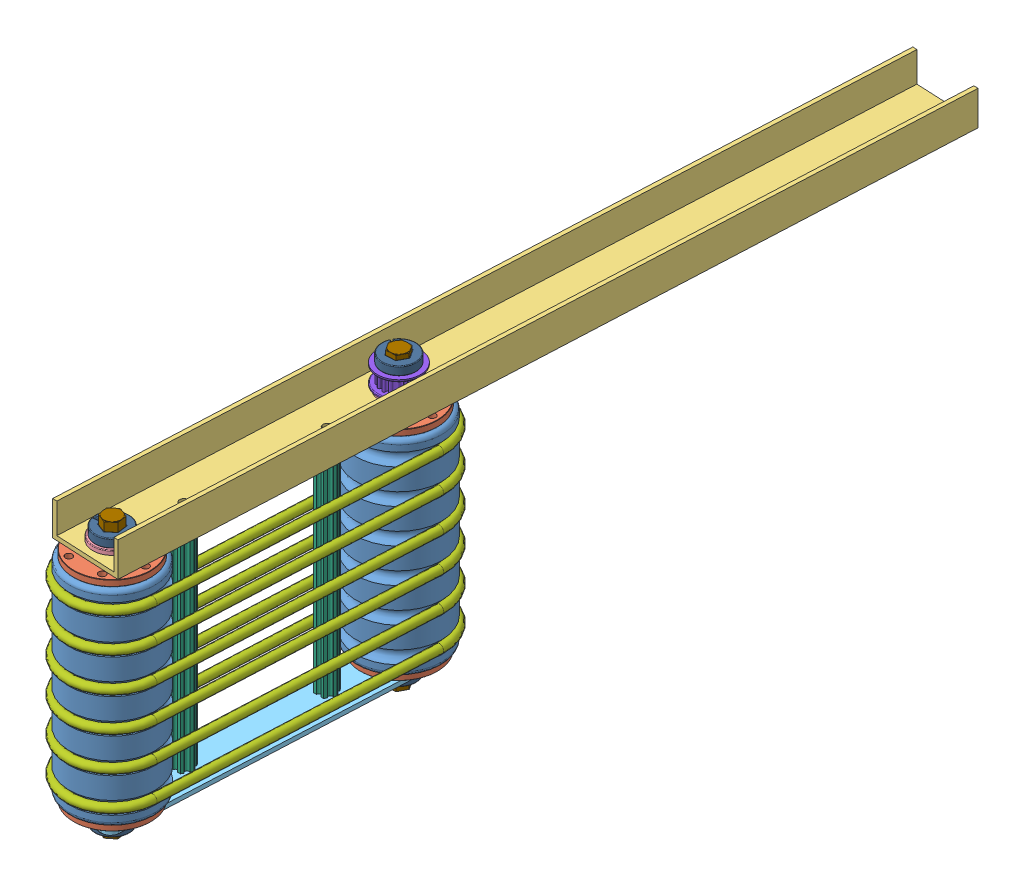
SolidWorks assembly Left_Arm, configuration Default. Lengths in mm.
Overall size (97.04 216.15 634.75).
27 component instances, 10 part files, 50 mates.
Components (placement in the parent):
- Roller-1: Roller [Default] at (106.9288 96.8013 440.1818) x (0.852613 0 0.522543) z (-0.522543 0 0.852613) size (63.5 152.4 63.5)
- am-0096a_Hex_Hub-1: am-0096a_Hex_Hub [Default] at (106.9288 235.2773 440.1818) x (0 -1 0) z (0.466376 0 -0.884587) size (25.4 57.15 57.15)
- am-0096a_Hex_Hub-2: am-0096a_Hex_Hub [Default] at (106.9288 110.7254 440.1818) x (0 1 0) z (-0.532886 0 -0.846187) size (25.4 57.15 57.15)
- Arm-1: Arm [Default] at (109.5659 256.1863 -150.9083) x (0.998875 0 0.047428) z (-0.047428 0 0.998875) size (50.8 25.4 609.6)
- Hex_Bearing-1: Hex_Bearing [Default] at (106.9288 262.5897 440.1818) x (-0.824482 0 0.565888) z (0 -1 0) size (31.12 31.12 7.93)
- Hex_Bearing-2: Hex_Bearing [Default] at (116.5661 262.5897 237.2105) x (-0.838312 0 -0.545191) z (0 -1 0) size (31.12 31.12 7.93)
- am-0096a_Hex_Hub-3: am-0096a_Hex_Hub [Default] at (116.5661 235.2773 237.2105) x (0 -1 0) z (0.466376 0 -0.884587) size (25.4 57.15 57.15)
- Roller-2: Roller [Default] at (116.5661 96.8013 237.2105) x (0.971171 0 -0.238383) z (0.238383 0 0.971171) size (63.5 152.4 63.5)
- am-0096a_Hex_Hub-4: am-0096a_Hex_Hub [Default] at (116.5661 110.7254 237.2105) x (0 1 0) z (-0.532886 0 -0.846187) size (25.4 57.15 57.15)
- Hex_Bearing-3: Hex_Bearing [Default] at (106.9288 83.413 440.1818) x (0.999998 0 0.002092) z (0 1 0) size (31.12 31.12 7.93)
- Hex_Bearing-4: Hex_Bearing [Default] at (116.5661 83.413 237.2105) x (-0.08884 0 -0.996046) z (0 1 0) size (31.12 31.12 7.93)
- Arm_Lowwer-1: Arm_Lowwer [Default] at (106.9288 86.6413 440.1818) x (0.047428 0 -0.998875) z (0.998875 0 0.047428) size (241.3 3.17 38.1)
- Claw_Churo-1: Claw_Churo [Default] at (109.3381 256.1863 389.439) x (1 0 0) z (0 -1 0) size (14.66 12.7 166.37)
- Claw_Churo-2: Claw_Churo [Default] at (114.1568 256.1863 287.9533) x (1 0 0) z (0 -1 0) size (14.66 12.7 166.37)
- Polycord-1: Polycord [Default] at (106.9288 236.4297 440.1818) x (0.047428 0 -0.998875) z (0.998875 0 0.047428) size (273.05 6.35 69.85)
- Sproket_Small_-1: Sproket_Small_ [Default] at (116.5661 275.0992 237.2105) x (0.998884 0 -0.047227) z (0 -1 0) size (32 32 14.1)
- Polycord-2: Polycord [Default] at (106.9288 211.0297 440.1818) x (0.047428 0 -0.998875) z (0.998875 0 0.047428) size (273.05 6.35 69.85)
- Polycord-3: Polycord [Default] at (106.9288 185.6297 440.1818) x (0.047428 0 -0.998875) z (0.998875 0 0.047428) size (273.05 6.35 69.85)
- Polycord-4: Polycord [Default] at (106.9288 160.2297 440.1818) x (0.047428 0 -0.998875) z (0.998875 0 0.047428) size (273.05 6.35 69.85)
- Polycord-5: Polycord [Default] at (106.9288 134.8297 440.1818) x (0.047428 0 -0.998875) z (0.998875 0 0.047428) size (273.05 6.35 69.85)
- Polycord-6: Polycord [Default] at (106.9288 109.4297 440.1818) x (0.047428 0 -0.998875) z (0.998875 0 0.047428) size (273.05 6.35 69.85)
- Hex_Shaft1-1: Hex_Shaft1 [Default] at (106.9288 71.8357 440.1818) x (0.47039 0 -0.882459) z (0.882459 0 0.47039) size (13.45 203.45 14.57)
- Hex_Collar-1: Hex_Collar [Default] at (106.9288 262.5897 440.1818) x (-0.147489 0 -0.989064) z (0.989064 0 -0.147489) size (25.4 6.35 25.42)
- Hex_Collar-2: Hex_Collar [Default] at (106.9288 77.063 440.1818) x (-0.930299 0 -0.366802) z (0.366802 0 -0.930299) size (25.4 6.35 25.42)
- Hex_Shaft1-2: Hex_Shaft1 [Extra_Long] at (116.5661 70.0577 237.2105) x (-0.066869 0 0.997762) z (-0.997762 0 -0.066869) size (13.45 216.15 14.57)
- Hex_Collar-3: Hex_Collar [Default] at (116.5661 276.6867 237.2105) x (0.458542 0 -0.888673) z (0.888673 0 0.458542) size (25.4 6.35 25.42)
- Hex_Collar-4: Hex_Collar [Default] at (116.5661 77.063 237.2105) x (0.458542 0 -0.888673) z (0.888673 0 0.458542) size (25.4 6.35 25.42)
Mates (geometry in assembly coordinates):
- Coincident1: coincident anti-aligned: plane of Roller-1 through (106.9288 249.2013 440.1818) normal (0 1 0); plane of am-0096a_Hex_Hub-1 through (109.5994 249.2013 435.1164) normal (0 -1 0)
- Concentric1: concentric aligned: circle of Roller-1; circle of am-0096a_Hex_Hub-1
- Coincident2: coincident anti-aligned: plane of Roller-1 through (106.9288 96.8013 440.1818) normal (0 -1 0); plane of am-0096a_Hex_Hub-2 through (103.8773 96.8013 435.3362) normal (0 1 0)
- Concentric2: concentric aligned: circle of Roller-1; circle of am-0096a_Hex_Hub-2
- Concentric15: concentric anti-aligned: circle of Roller-1; circle of Polycord-1
- Parallel1: parallel aligned: plane of am-0096a_Hex_Hub-1 through (100.4168 254.6623 436.7485) normal (0.532886 0 0.846187); plane of am-0096a_Hex_Hub-2 through (106.6461 91.3403 432.8256) normal (0.532886 0 0.846187)
- Coincident10: coincident anti-aligned: plane of am-0096a_Hex_Hub-1 through (106.9288 254.6623 440.1818) normal (0 1 0); plane of Hex_Bearing-1 through (94.2066 254.6623 448.9138) normal (0 -1 0)
- Concentric3: concentric anti-aligned: circle of am-0096a_Hex_Hub-1; circle of Hex_Bearing-1
- Coincident17: coincident anti-aligned: plane of am-0096a_Hex_Hub-2 through (106.9288 91.3403 440.1818) normal (0 -1 0); plane of Hex_Bearing-3 through (122.3592 91.3403 440.2141) normal (0 1 0)
- Concentric9: concentric aligned: circle of am-0096a_Hex_Hub-2; circle of Hex_Bearing-3
- Concentric4: concentric anti-aligned: circle of Arm-1; circle of Hex_Bearing-1
- Coincident11: coincident anti-aligned: plane of Arm-1 through (80.6539 256.1863 458.0057) normal (0 -1 0); plane of Hex_Bearing-1 through (95.4108 256.1863 448.0873) normal (0 1 0)
- Concentric5: concentric anti-aligned: circle of Arm-1; circle of Hex_Bearing-2
- Coincident13: coincident anti-aligned: plane of Arm-1 through (80.6539 256.1863 458.0057) normal (0 -1 0); plane of Hex_Bearing-2 through (104.8549 256.1863 229.5942) normal (0 1 0)
- Coincident14: coincident anti-aligned: plane of Hex_Bearing-2 through (103.6305 254.6623 228.7979) normal (0 -1 0); plane of am-0096a_Hex_Hub-3 through (116.5661 254.6623 237.2105) normal (0 1 0)
- Concentric6: concentric anti-aligned: circle of Hex_Bearing-2; circle of am-0096a_Hex_Hub-3
- Coincident22: coincident anti-aligned: plane of Hex_Bearing-2 through (116.5661 262.5897 237.2105) normal (0 1 0); plane of Sproket_Small_-1 through (116.5661 262.5897 237.2105) normal (0 -1 0)
- Concentric17: concentric aligned: circle of Hex_Bearing-2; circle of Sproket_Small_-1
- Concentric7: concentric aligned: circle of am-0096a_Hex_Hub-3; circle of Roller-2
- Coincident15: coincident anti-aligned: plane of am-0096a_Hex_Hub-3 through (119.2368 249.2013 232.145) normal (0 -1 0); plane of Roller-2 through (116.5661 249.2013 237.2105) normal (0 1 0)
- Concentric8: concentric aligned: circle of Roller-2; circle of am-0096a_Hex_Hub-4
- Coincident16: coincident anti-aligned: plane of Roller-2 through (116.5661 96.8013 237.2105) normal (0 -1 0); plane of am-0096a_Hex_Hub-4 through (113.5146 96.8013 232.3649) normal (0 1 0)
- Concentric16: concentric anti-aligned: circle of Roller-2; circle of Polycord-1
- Concentric10: concentric anti-aligned: circle of am-0096a_Hex_Hub-4; circle of Hex_Bearing-4
- Coincident18: coincident anti-aligned: plane of am-0096a_Hex_Hub-4 through (116.5661 91.3403 237.2105) normal (0 -1 0); plane of Hex_Bearing-4 through (115.1953 91.3403 221.841) normal (0 1 0)
- Concentric11: concentric aligned: circle of Hex_Bearing-3; circle of Arm_Lowwer-1
- Coincident19: coincident anti-aligned: plane of Hex_Bearing-3 through (120.8987 89.8163 440.2111) normal (0 -1 0); plane of Arm_Lowwer-1 through (129.8541 89.8163 225.1271) normal (0 1 0)
- Concentric12: concentric aligned: circle of Hex_Bearing-4; circle of Arm_Lowwer-1
- Coincident20: coincident anti-aligned: plane of Arm_Lowwer-1 through (129.8541 89.8163 225.1271) normal (0 1 0); plane of Claw_Churo-1 through (114.8374 89.8163 386.264) normal (0 -1 0)
- Concentric13: concentric aligned: circle of Arm_Lowwer-1; circle of Claw_Churo-1
- Coincident21: coincident anti-aligned: plane of Arm_Lowwer-1 through (129.8541 89.8163 225.1271) normal (0 1 0); plane of Claw_Churo-2 through (119.656 89.8163 284.7783) normal (0 -1 0)
- Concentric14: concentric aligned: circle of Arm_Lowwer-1; circle of Claw_Churo-2
- Concentric18: concentric aligned: circle of Hex_Bearing-1; circle of Hex_Shaft1-1
- Parallel5: parallel: line of Hex_Bearing-1 through (113.7501 262.5897 442.8714) axis (-0.147489 0 -0.989064); plane of Hex_Shaft1-1 through (113.7501 275.0357 442.8714) normal (0.989064 0 -0.147489)
- Coincident23: coincident anti-aligned: plane of Hex_Bearing-1 through (106.9288 262.5897 440.1818) normal (0 1 0); plane of Hex_Collar-1 through (106.9288 262.5897 440.1818) normal (0 -1 0)
- Concentric19: concentric anti-aligned: circle of Hex_Shaft1-1; circle of Hex_Collar-1
- Parallel13: parallel: plane of Hex_Shaft1-1 through (113.7501 275.0357 442.8714) normal (0.989064 0 -0.147489); line of Hex_Collar-1 through (113.1278 268.9397 435.2542) axis (0.147489 0 0.989064)
- Distance5: distance = 6.35 mm aligned: plane of Hex_Collar-1 through (106.9288 268.9397 440.1818) normal (0 1 0); plane of Hex_Shaft1-1 through (106.9288 275.2897 440.1818) normal (0 1 0)
- Concentric20: concentric aligned: circle of Hex_Bearing-3; circle of Hex_Collar-2
- Coincident24: coincident anti-aligned: plane of Hex_Bearing-3 through (106.9288 83.413 440.1818) normal (0 -1 0); plane of Hex_Collar-2 through (106.9288 83.413 440.1818) normal (0 1 0)
- Parallel14: parallel aligned: line of Hex_Shaft1-1 through (100.1075 71.8357 437.4923) axis (0.147489 0 0.989064); line of Hex_Collar-2 through (99.5618 77.063 437.2771) axis (0.147489 0 0.989064)
- Concentric21: concentric anti-aligned: circle of Roller-2; circle of Hex_Shaft1-2
- Parallel10: parallel: line of Sproket_Small_-1 through (123.8903 276.6867 236.8642) axis (-0.458542 0 0.888673); plane of Hex_Shaft1-2 through (120.5281 285.9577 243.3803) normal (0.888673 0 0.458542)
- Distance4: distance = 9.525 mm aligned: plane of Hex_Shaft1-2 through (116.5661 286.2117 237.2105) normal (0 1 0); plane of Sproket_Small_-1 through (116.5661 276.6867 237.2105) normal (0 1 0)
- Coincident25: coincident anti-aligned: plane of Sproket_Small_-1 through (116.5661 276.6867 237.2105) normal (0 1 0); plane of Hex_Collar-3 through (116.5661 276.6867 237.2105) normal (0 -1 0)
- Concentric22: concentric anti-aligned: circle of Hex_Shaft1-2; circle of Hex_Collar-3
- Parallel15: parallel anti-aligned: line of Hex_Shaft1-2 through (116.2662 285.9577 230.8676) axis (-0.998884 0 0.047227); line of Hex_Collar-3 through (112.2872 283.0367 230.5471) axis (0.998884 0 -0.047227)
- Concentric23: concentric aligned: circle of Hex_Bearing-4; circle of Hex_Collar-4
- Coincident26: coincident anti-aligned: plane of Hex_Bearing-4 through (116.5661 83.413 237.2105) normal (0 -1 0); plane of Hex_Collar-4 through (116.5661 83.413 237.2105) normal (0 1 0)
- Parallel16: parallel aligned: line of Hex_Shaft1-2 through (120.5281 70.0577 243.3803) axis (0.458542 0 -0.888673); line of Hex_Collar-4 through (120.845 77.063 243.8739) axis (0.458542 0 -0.888673)
